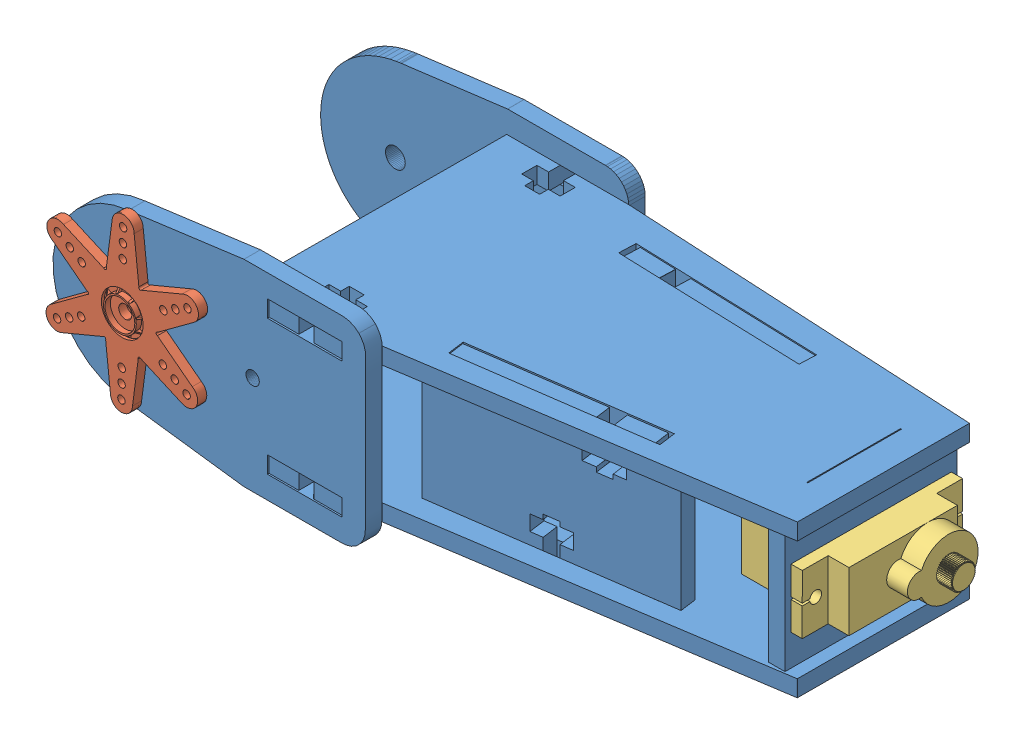
SolidWorks assembly left_forearm, configuration Default. Lengths in mm.
Overall size (161.87 49.09 61.84).
3 component instances, 3 part files, 2 mates.
Components (placement in the parent):
- left_forearm_100-1: left_forearm_100 [Default] at (68.3868 73.816 160.8972) x (0.000428 -0.002739 -0.999996) z (-0.001817 0.999995 -0.00274) size (59.26 143.71 48.67)
- servo_arm_6_sided-1: servo_arm_6_sided [Default] at (-59.0312 89.7707 161.137) x (-0.861784 0.507273 -0.001759) z (0.507276 0.861781 -0.002144) size (36.45 6.25 32.2)
- MG90S-1: MG90S [Default] at (48.5461 90.044 127.794) x (0.000428 -0.002739 -0.999996) z (0.00198 -0.999994 0.00274) size (34 30.4 12.5)
Mates (geometry in assembly coordinates):
- Concentric1: concentric aligned: circle of left_forearm_100-1; circle of servo_arm_6_sided-1
- Coincident1: coincident anti-aligned: line of left_forearm_100-1 through (64.5287 96.3574 139.3658) axis (0.000428 -0.002739 -0.999996); line of MG90S-1 through (64.5288 96.3571 139.2836) axis (-0.000428 0.002739 0.999996)
